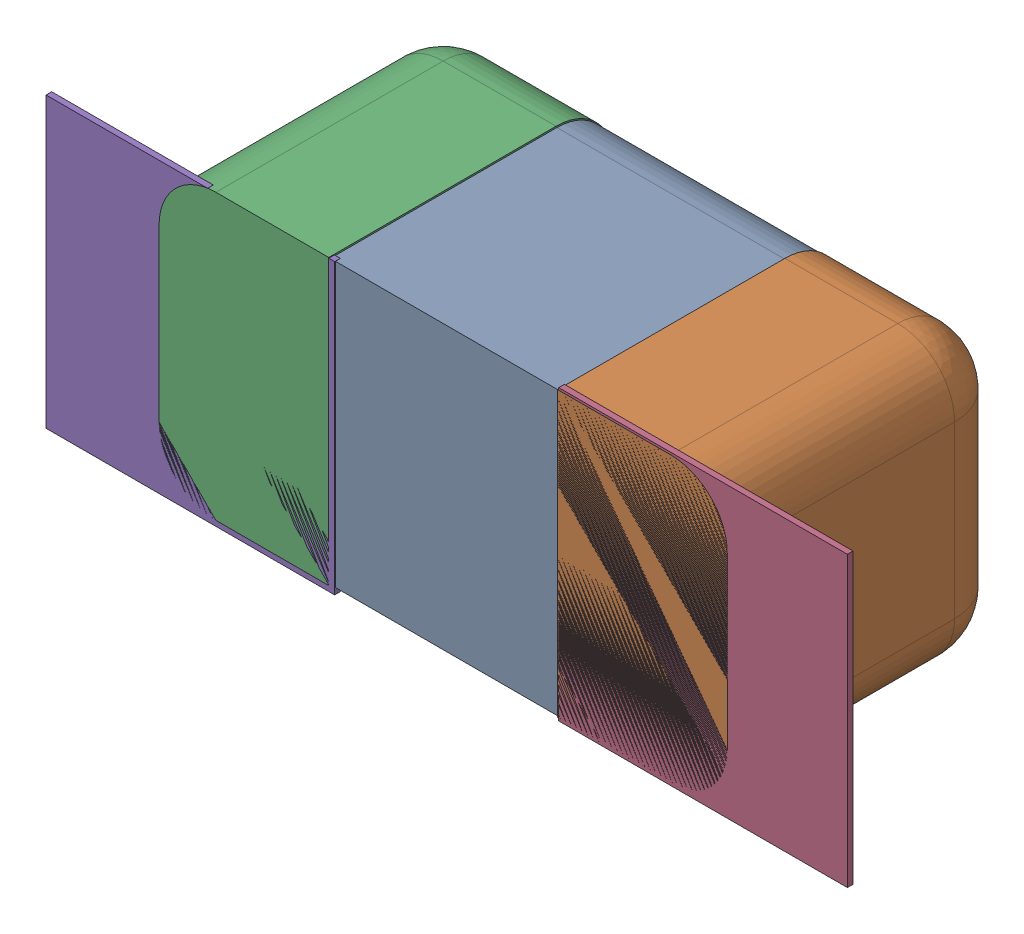
SolidWorks assembly C48, configuration Défaut. Lengths in mm.
Overall size (1.41 0.51 0.5).
8 component instances, 4 part files, 0 mates.
Components (placement in the parent):
- 6324936672-1: 6324936672 [Défaut] at (20.4655 -11.5331 -2.0818) x (-1 0 0) z (0 -1 0) size (1 0.5 0.5)
  - Open CASCADE STEP translator 7.5 2.131.1.1-1: Open CASCADE STEP translator 7.5 2.131.1.1 [Défaut] at origin size (0.4 0.5 0.5)
  - Open CASCADE STEP translator 7.5 2.131.1.2-1: Open CASCADE STEP translator 7.5 2.131.1.2 [Défaut] at origin size (0.3 0.5 0.5)
  - Open CASCADE STEP translator 7.5 2.131.1.3-1: Open CASCADE STEP translator 7.5 2.131.1.3 [Défaut] at origin size (0.3 0.5 0.5)
- 6504207776-1: 6504207776 [Défaut] at (20.9229 -11.5331 -2.0918) size (0.51 0.51 0.01)
  - Extruded-1: Extruded [Défaut] at origin size (0.51 0.51 0.01)
- 6504207776-2: 6504207776 [Défaut] at (20.0206 -11.5382 -2.0918) size (0.51 0.51 0.01)
  - Extruded-1: Extruded [Défaut] at origin size (0.51 0.51 0.01)
